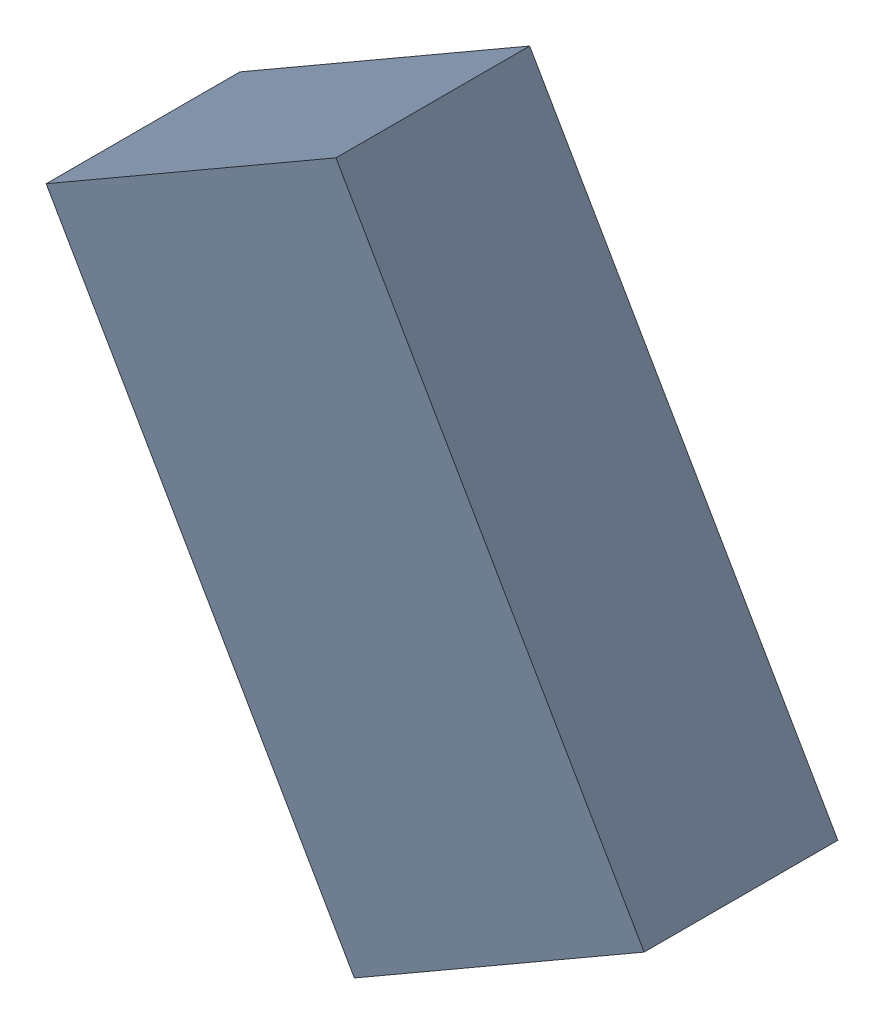
SolidWorks assembly L1_TDA5, configuration Standard. Lengths in mm.
Overall size (1.7 1.99 0.55).
2 component instances, 1 part files, 0 mates.
Components (placement in the parent):
- 885543464-1: 885543464 [Standard] at (-47.6151 -29.504 0) size (1.7 1.99 0.55)
  - Extruded_18-1: Extruded_18 [Standard] at origin size (1.7 1.99 0.55)
